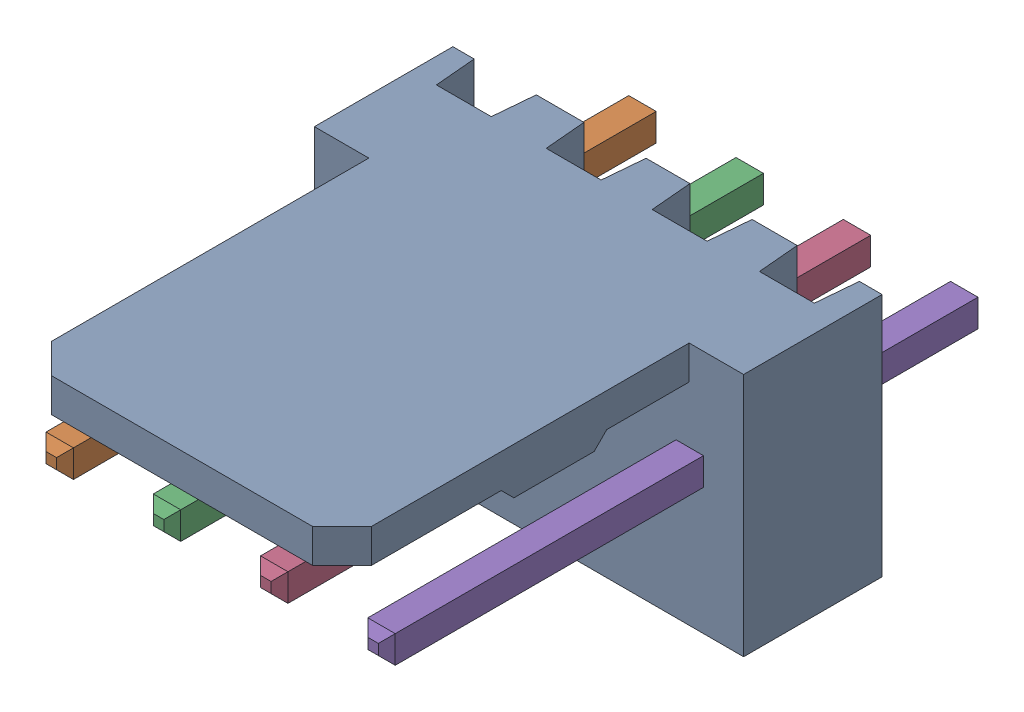
SolidWorks assembly Molex PCB 4 pin v3_4, configuration Default. Lengths in mm.
Overall size (10.16 5.79 14.92).
5 component instances, 2 part files, 0 mates.
Components (placement in the parent):
- BASE9710016-1: BASE9710016 [Default] at (2.54 2.895 -8.22) size (10.16 5.79 11.5)
- PINO9710016-1: PINO9710016 [Default] at (1.27 3.325 -0.72) size (0.65 0.65 14.2)
- PINO9710016-2: PINO9710016 [Default] at (3.81 3.325 -0.72) size (0.65 0.65 14.2)
- PINO9710016-3: PINO9710016 [Default] at (6.35 3.325 -0.72) size (0.65 0.65 14.2)
- PINO9710016-4: PINO9710016 [Default] at (8.89 3.325 -0.72) size (0.65 0.65 14.2)
